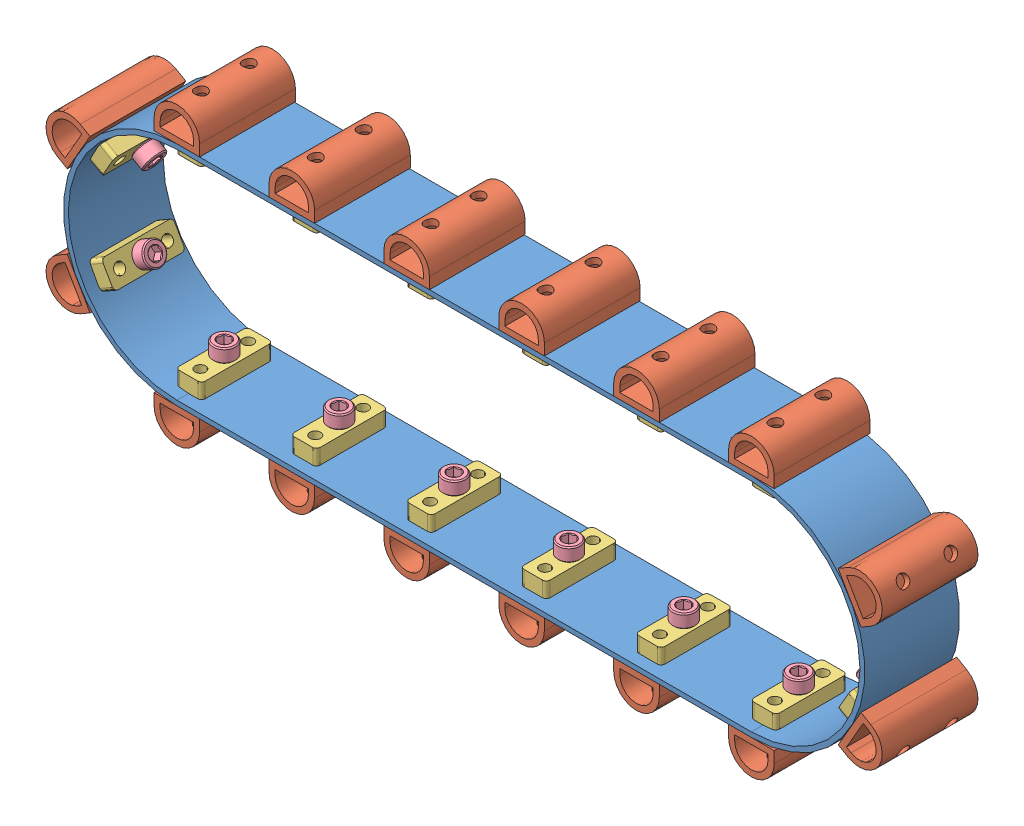
SolidWorks assembly tread, configuration Default. Lengths in mm.
Overall size (178.18 61.66 20).
65 component instances, 4 part files, 7 mates.
Components (placement in the parent):
- tread_base-1: tread_base [Default] at origin size (167.39 47.38 19.81)
- D-Lug_Terrain-1: D-Lug_Terrain [Default] at (0 48.7584 -10.094) size (9.53 7.14 20)
- D-Lug_Terrain-2: D-Lug_Terrain [Default] at (-22.5771 35.7234 -10.094) x (0.5 0.866025 0) z (0 0 1) size (9.53 7.14 20)
- D-Lug_Terrain-3: D-Lug_Terrain [Default] at (-22.5771 9.6536 -10.094) x (-0.5 0.866025 0) z (0 0 1) size (9.53 7.14 20)
- D-Lug_Terrain-4: D-Lug_Terrain [Default] at (0 -3.3813 -10.094) x (-1 0 0) z (0 0 1) size (9.53 7.14 20)
- D-Lug_Terrain-6: D-Lug_Terrain [Default] at (24.003 48.7584 -10.094) size (9.53 7.14 20)
- D-Lug_Terrain-7: D-Lug_Terrain [Default] at (48.006 48.7584 -10.094) size (9.53 7.14 20)
- D-Lug_Terrain-8: D-Lug_Terrain [Default] at (72.009 48.7584 -10.094) size (9.53 7.14 20)
- D-Lug_Terrain-9: D-Lug_Terrain [Default] at (96.012 48.7584 -10.094) size (9.53 7.14 20)
- D-Lug_Terrain-10: D-Lug_Terrain [Default] at (120.015 48.7584 -10.094) size (9.53 7.14 20)
- D-Lug_Terrain-11: D-Lug_Terrain [Default] at (24.003 -3.3813 -10.094) x (-1 0 0) z (0 0 1) size (9.53 7.14 20)
- D-Lug_Terrain-12: D-Lug_Terrain [Default] at (48.006 -3.3813 -10.094) x (-1 0 0) z (0 0 1) size (9.53 7.14 20)
- D-Lug_Terrain-13: D-Lug_Terrain [Default] at (72.009 -3.3813 -10.094) x (-1 0 0) z (0 0 1) size (9.53 7.14 20)
- D-Lug_Terrain-14: D-Lug_Terrain [Default] at (96.012 -3.3813 -10.094) x (-1 0 0) z (0 0 1) size (9.53 7.14 20)
- D-Lug_Terrain-15: D-Lug_Terrain [Default] at (142.5921 35.7234 -10.094) x (0.5 -0.866025 0) z (0 0 1) size (9.53 7.14 20)
- D-Lug_Terrain-16: D-Lug_Terrain [Default] at (142.5921 9.6536 -10.094) x (-0.5 -0.866025 0) z (0 0 1) size (9.53 7.14 20)
- D-Lug_Terrain-17: D-Lug_Terrain [Default] at (120.015 -3.3813 -10.094) x (-1 0 0) z (0 0 1) size (9.53 7.14 20)
- DriveLug_x-1: DriveLug_x [Default] at (-2.7045 0 0) size (5.84 6.24 14.92)
  - Drive Lug_x-1: Drive Lug_x [Default] at origin size (5.41 3.2 14.92)
  - 97334A104_NYLON SOCKET HEAD CAP SCREW-1: 97334A104_NYLON SOCKET HEAD CAP SCREW [97334A104] at (2.7045 0.0254 0) x (0.302379 0 0.953188) z (0 -1 0) size (4.65 4.65 6.24)
- DriveLug_x-2: DriveLug_x [Default] at (-21.0011 13.6864 0) x (0.5 -0.866025 0) z (0 0 1) size (5.84 6.24 14.92)
  - Drive Lug_x-1: Drive Lug_x [Default] at origin size (5.41 3.2 14.92)
  - 97334A104_NYLON SOCKET HEAD CAP SCREW-1: 97334A104_NYLON SOCKET HEAD CAP SCREW [97334A104] at (2.7045 0.0254 0) x (0.302379 0 0.953188) z (0 -1 0) size (4.65 4.65 6.24)
- DriveLug_x-3: DriveLug_x [Default] at (-18.2966 36.375 0) x (-0.5 -0.866025 0) z (0 0 1) size (5.84 6.24 14.92)
  - Drive Lug_x-1: Drive Lug_x [Default] at origin size (5.41 3.2 14.92)
  - 97334A104_NYLON SOCKET HEAD CAP SCREW-1: 97334A104_NYLON SOCKET HEAD CAP SCREW [97334A104] at (2.7045 0.0254 0) x (0.302379 0 0.953188) z (0 -1 0) size (4.65 4.65 6.24)
- DriveLug_x-4: DriveLug_x [Default] at (2.7045 45.3771 0) x (-1 0 0) z (0 0 1) size (5.84 6.24 14.92)
  - Drive Lug_x-1: Drive Lug_x [Default] at origin size (5.41 3.2 14.92)
  - 97334A104_NYLON SOCKET HEAD CAP SCREW-1: 97334A104_NYLON SOCKET HEAD CAP SCREW [97334A104] at (2.7045 0.0254 0) x (0.302379 0 0.953188) z (0 -1 0) size (4.65 4.65 6.24)
- DriveLug_x-5: DriveLug_x [Default] at (21.2985 0 0) size (5.84 6.24 14.92)
  - Drive Lug_x-1: Drive Lug_x [Default] at origin size (5.41 3.2 14.92)
  - 97334A104_NYLON SOCKET HEAD CAP SCREW-1: 97334A104_NYLON SOCKET HEAD CAP SCREW [97334A104] at (2.7045 0.0254 0) x (0.302379 0 0.953188) z (0 -1 0) size (4.65 4.65 6.24)
- DriveLug_x-6: DriveLug_x [Default] at (45.3015 0 0) size (5.84 6.24 14.92)
  - Drive Lug_x-1: Drive Lug_x [Default] at origin size (5.41 3.2 14.92)
  - 97334A104_NYLON SOCKET HEAD CAP SCREW-1: 97334A104_NYLON SOCKET HEAD CAP SCREW [97334A104] at (2.7045 0.0254 0) x (0.302379 0 0.953188) z (0 -1 0) size (4.65 4.65 6.24)
- DriveLug_x-7: DriveLug_x [Default] at (69.3045 0 0) size (5.84 6.24 14.92)
  - Drive Lug_x-1: Drive Lug_x [Default] at origin size (5.41 3.2 14.92)
  - 97334A104_NYLON SOCKET HEAD CAP SCREW-1: 97334A104_NYLON SOCKET HEAD CAP SCREW [97334A104] at (2.7045 0.0254 0) x (0.302379 0 0.953188) z (0 -1 0) size (4.65 4.65 6.24)
- DriveLug_x-8: DriveLug_x [Default] at (93.3075 0 0) size (5.84 6.24 14.92)
  - Drive Lug_x-1: Drive Lug_x [Default] at origin size (5.41 3.2 14.92)
  - 97334A104_NYLON SOCKET HEAD CAP SCREW-1: 97334A104_NYLON SOCKET HEAD CAP SCREW [97334A104] at (2.7045 0.0254 0) x (0.302379 0 0.953188) z (0 -1 0) size (4.65 4.65 6.24)
- DriveLug_x-9: DriveLug_x [Default] at (117.3105 0 0) size (5.84 6.24 14.92)
  - Drive Lug_x-1: Drive Lug_x [Default] at origin size (5.41 3.2 14.92)
  - 97334A104_NYLON SOCKET HEAD CAP SCREW-1: 97334A104_NYLON SOCKET HEAD CAP SCREW [97334A104] at (2.7045 0.0254 0) x (0.302379 0 0.953188) z (0 -1 0) size (4.65 4.65 6.24)
- DriveLug_x-10: DriveLug_x [Default] at (138.3116 9.0021 0) x (0.5 0.866025 0) z (0 0 1) size (5.84 6.24 14.92)
  - Drive Lug_x-1: Drive Lug_x [Default] at origin size (5.41 3.2 14.92)
  - 97334A104_NYLON SOCKET HEAD CAP SCREW-1: 97334A104_NYLON SOCKET HEAD CAP SCREW [97334A104] at (2.7045 0.0254 0) x (0.302379 0 0.953188) z (0 -1 0) size (4.65 4.65 6.24)
- DriveLug_x-11: DriveLug_x [Default] at (141.0161 31.6907 0) x (-0.5 0.866025 0) z (0 0 1) size (5.84 6.24 14.92)
  - Drive Lug_x-1: Drive Lug_x [Default] at origin size (5.41 3.2 14.92)
  - 97334A104_NYLON SOCKET HEAD CAP SCREW-1: 97334A104_NYLON SOCKET HEAD CAP SCREW [97334A104] at (2.7045 0.0254 0) x (0.302379 0 0.953188) z (0 -1 0) size (4.65 4.65 6.24)
- DriveLug_x-12: DriveLug_x [Default] at (122.7195 45.3771 0) x (-1 0 0) z (0 0 1) size (5.84 6.24 14.92)
  - Drive Lug_x-1: Drive Lug_x [Default] at origin size (5.41 3.2 14.92)
  - 97334A104_NYLON SOCKET HEAD CAP SCREW-1: 97334A104_NYLON SOCKET HEAD CAP SCREW [97334A104] at (2.7045 0.0254 0) x (0.302379 0 0.953188) z (0 -1 0) size (4.65 4.65 6.24)
- DriveLug_x-13: DriveLug_x [Default] at (26.7075 45.3771 0) x (-1 0 0) z (0 0 1) size (5.84 6.24 14.92)
  - Drive Lug_x-1: Drive Lug_x [Default] at origin size (5.41 3.2 14.92)
  - 97334A104_NYLON SOCKET HEAD CAP SCREW-1: 97334A104_NYLON SOCKET HEAD CAP SCREW [97334A104] at (2.7045 0.0254 0) x (0.302379 0 0.953188) z (0 -1 0) size (4.65 4.65 6.24)
- DriveLug_x-14: DriveLug_x [Default] at (50.7105 45.3771 0) x (-1 0 0) z (0 0 1) size (5.84 6.24 14.92)
  - Drive Lug_x-1: Drive Lug_x [Default] at origin size (5.41 3.2 14.92)
  - 97334A104_NYLON SOCKET HEAD CAP SCREW-1: 97334A104_NYLON SOCKET HEAD CAP SCREW [97334A104] at (2.7045 0.0254 0) x (0.302379 0 0.953188) z (0 -1 0) size (4.65 4.65 6.24)
- DriveLug_x-15: DriveLug_x [Default] at (74.7135 45.3771 0) x (-1 0 0) z (0 0 1) size (5.84 6.24 14.92)
  - Drive Lug_x-1: Drive Lug_x [Default] at origin size (5.41 3.2 14.92)
  - 97334A104_NYLON SOCKET HEAD CAP SCREW-1: 97334A104_NYLON SOCKET HEAD CAP SCREW [97334A104] at (2.7045 0.0254 0) x (0.302379 0 0.953188) z (0 -1 0) size (4.65 4.65 6.24)
- DriveLug_x-16: DriveLug_x [Default] at (98.7165 45.3771 0) x (-1 0 0) z (0 0 1) size (5.84 6.24 14.92)
  - Drive Lug_x-1: Drive Lug_x [Default] at origin size (5.41 3.2 14.92)
  - 97334A104_NYLON SOCKET HEAD CAP SCREW-1: 97334A104_NYLON SOCKET HEAD CAP SCREW [97334A104] at (2.7045 0.0254 0) x (0.302379 0 0.953188) z (0 -1 0) size (4.65 4.65 6.24)
Mates (geometry in assembly coordinates):
- Coincident2: coincident: plane of tread_base-1 through (0 46.3771 9.906) normal (0 1 0); plane of D-Lug_Terrain-1 through (-4.7625 46.3771 9.906) normal (0 -1 0)
- Coincident3: coincident: plane of tread_base-1 through (120.015 22.6885 9.906) normal (0 0 1); plane of D-Lug_Terrain-1 through (0 48.7584 9.906) normal (0 0 1)
- Coincident6: coincident: point of tread_base-1; point of D-Lug_Terrain-1
- Coincident7: coincident: plane of tread_base-1 through (0 0 9.906) normal (0 1 0); plane of DriveLug_x-1/Drive Lug_x-1 through (-2.7045 0 7.46) normal (0 -1 0)
- Coincident8: coincident: line of tread_base-1 through (120.015 0 0) axis (0 1 0); point of DriveLug_x-1/Drive Lug_x-1
- Parallel2: parallel: plane of tread_base-1 through (120.015 22.6885 9.906) normal (0 0 1); plane of DriveLug_x-1/Drive Lug_x-1 through (-2.7045 0 7.46) normal (0 0 1)
- Coincident13: coincident: line of tread_base-1 through (0 0 9.906) axis (0 0 -1); point of DriveLug_x-1/Drive Lug_x-1
